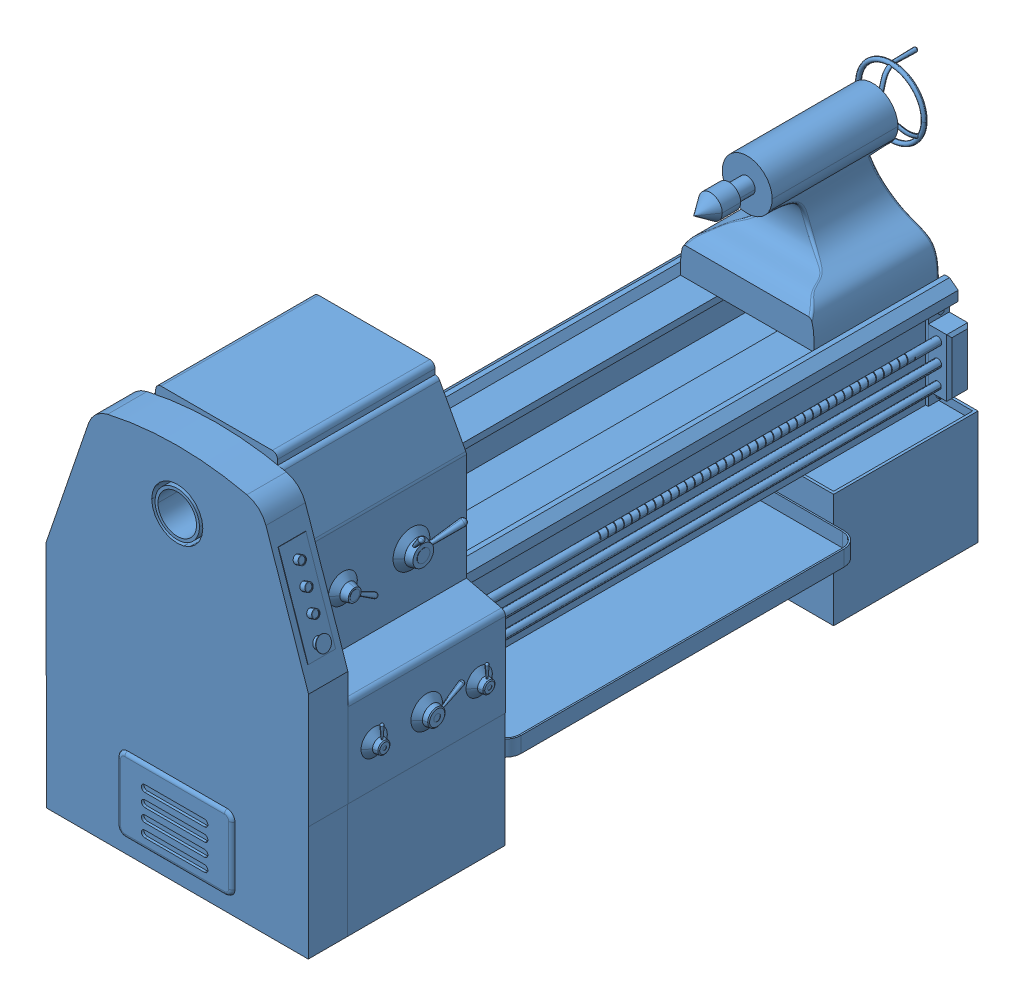
SolidWorks assembly 20180320-150305-21510.STEP, configuration 默认. Lengths in mm.
Overall size (1042.03 1459.87 2827.09).
7 component instances, 5 part files, 0 mates.
Components (placement in the parent):
- CY6140____.STEP-1: CY6140____.STEP [默认] at (78.913 -28.977 267.5921) size (1148.43 1459.87 2827.09)
  - CY6140________.STEP-1: CY6140________.STEP [默认] at (-628.9751 138.378 1403.5468) size (1042.03 1459.87 2827.09)
  - CY6140________-0.STEP-1: CY6140________-0.STEP [默认] at (-628.9751 138.378 1815.3981) size (987.43 871.86 582.56) (hidden)
  - r23fwerwfe.STEP-1: r23fwerwfe.STEP [默认] at (-25.4859 413.562 486.7925) x (-1 0 0) z (0 0 -1) size (20 20 150) (hidden)
  - r23fwerwfe.STEP-2: r23fwerwfe.STEP [默认] at (-232.4642 393.562 486.7925) x (1 0 0) z (0 0 -1) size (20 20 150) (hidden)
- t42frwfgrw.STEP-1: t42frwfgrw.STEP [默认] at (-50.062 454.8357 814.4975) x (-0.146752 0.989173 0) z (0 0 1) size (225 225 7) (hidden)
- r245f5rre.STEP-1: r245f5rre.STEP [默认] at (-50.062 454.8357 835.4975) x (0.514008 0.857785 0) z (0 0 -1) size (192.99 192.99 65) (hidden)
